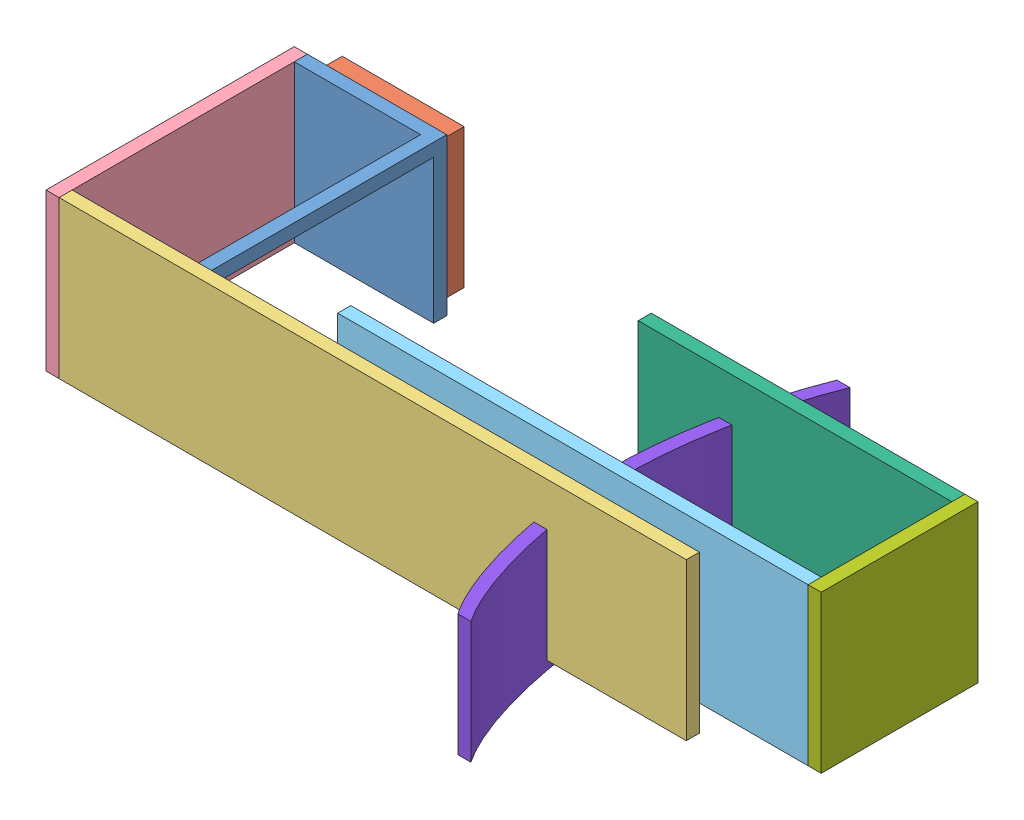
SolidWorks assembly Assem2, configuration Default. Lengths in mm.
Overall size (2145.74 482.6 1143).
8 component instances, 8 part files, 24 mates.
Components (placement in the parent):
- Part 1-1: Part 1 [Default] at (-25.4 -20.32 76.2) size (406.4 457.2 685.8)
- Part 1-1-1: Part 1-1 [Default] at origin size (355.6 406.4 76.2)
- Part 1-2-1: Part 1-2 [Default] at (1803.4 -20.32 762) size (1828.8 457.2 38.1)
- Part 1-3-1: Part 1-3 [Default] at (-63.5 436.88 114.3) size (38.1 457.2 723.9)
- Part 1-4-1: Part 1-4 [Default] at (2044.142 -20.32 647.7) size (1371.6 457.2 38.1)
- Part 1-5-1: Part 1-5 [Default] at (2044.142 -20.32 228.6) size (914.4 457.2 38.1)
- Part 1-6-2: Part 1-6 [Default] at (2044.142 436.88 228.6) size (38.1 457.2 457.2)
- Part 1-7-1: Part 1-7 [Default] at (1442.3322 309.88 0) size (249.86 355.6 1143)
Mates (geometry in assembly coordinates):
- Coincident3: coincident anti-aligned: plane of ? through (2052.8691 208.28 685.8) normal (1 0 0); plane of ? through (2052.8691 -20.32 419.1) normal (-1 0 0)
- Coincident5: coincident anti-aligned: plane of ? through (2052.8691 208.28 266.7) normal (1 0 0); plane of ? through (2052.8691 -20.32 419.1) normal (-1 0 0)
- Coincident6: coincident anti-aligned: plane of Part 1-1 through (177.8 208.28 76.2) normal (0 0 -1); plane of Part 1-1-1 through (177.8 203.2 76.2) normal (0 0 1)
- Coincident7: coincident anti-aligned: plane of Part 1-1 through (-25.4 208.28 114.3) normal (-1 0 0); plane of Part 1-3-1 through (-25.4 208.28 457.2) normal (1 0 0)
- Coincident8: coincident anti-aligned: plane of Part 1-2-1 through (-25.4 208.28 800.1) normal (-1 0 0); plane of Part 1-3-1 through (-25.4 208.28 457.2) normal (1 0 0)
- Coincident9: coincident anti-aligned: plane of Part 1-1 through (177.8 208.28 762) normal (0 0 1); plane of Part 1-2-1 through (889 208.28 762) normal (0 0 -1)
- Coincident10: coincident anti-aligned: plane of Part 1-2-1 through (889 132.08 781.05) normal (0 -1 0); plane of Part 1-7-1 through (1393.6031 132.08 571.5) normal (0 1 0)
- Coincident11: coincident anti-aligned: plane of ? through (1367.0691 132.08 666.75) normal (0 -1 0); plane of Part 1-7-1 through (1393.6031 132.08 571.5) normal (0 1 0)
- Coincident12: coincident anti-aligned: plane of ? through (1595.6691 132.08 247.65) normal (0 -1 0); plane of Part 1-7-1 through (1393.6031 132.08 571.5) normal (0 1 0)
- Parallel2: parallel aligned: plane of Part 1-1-1 through (177.8 203.2 0) normal (0 0 -1); plane of Part 1-7-1 through (1487.0808 -45.72 0) normal (0 0 -1)
- Coincident13: coincident: point of Part 1-1-1
- Coincident14: coincident: point of ?; point of ?
- Coincident15: coincident: point of ?; point of ?
- Coincident16: coincident: point of Part 1-1; point of Part 1-3-1
- Coincident17: coincident: point of Part 1-2-1; point of Part 1-3-1
- Coincident18: coincident anti-aligned: plane of ? through (1595.6691 208.28 228.6) normal (0 0 -1); plane of Part 1-7-1 through (1371.1723 132.08 228.6) normal (0 0 1)
- Parallel4: parallel aligned: plane of Part 1-3-1 through (-25.4 -20.32 457.2) normal (0 -1 0); plane of ? through (1497.3465 -20.32 266.7) normal (0 -1 0)
- Distance2: distance = 381 mm: line of Part 1-1-1 through (0 0 76.2) axis (0 1 0); line of Part 1-1 through (381 -20.32 76.2) axis (0 1 0)
- Distance3: distance = 30.48 mm: line of Part 1-1-1 through (0 406.4 76.2) axis (1 0 0); line of Part 1-1 through (-25.4 436.88 76.2) axis (1 0 0)
- Coincident23: coincident anti-aligned: plane of Part 1-1-1 through (177.8 203.2 0) normal (0 0 -1)
- Parallel6: parallel anti-aligned: plane of Part 1-3-1 through (-63.5 208.28 457.2) normal (-1 0 0)
- Coincident25: coincident anti-aligned: plane of Part 1-2-1 through (889 208.28 762) normal (0 0 -1); plane of Part 1-7-1 through (1442.9107 132.08 762) normal (0 0 1)
- Coincident26: coincident: point of Part 1-2-1; point of Part 1-7-1
- Coincident27: coincident: point of Part 1-5-1; point of Part 1-7-1
